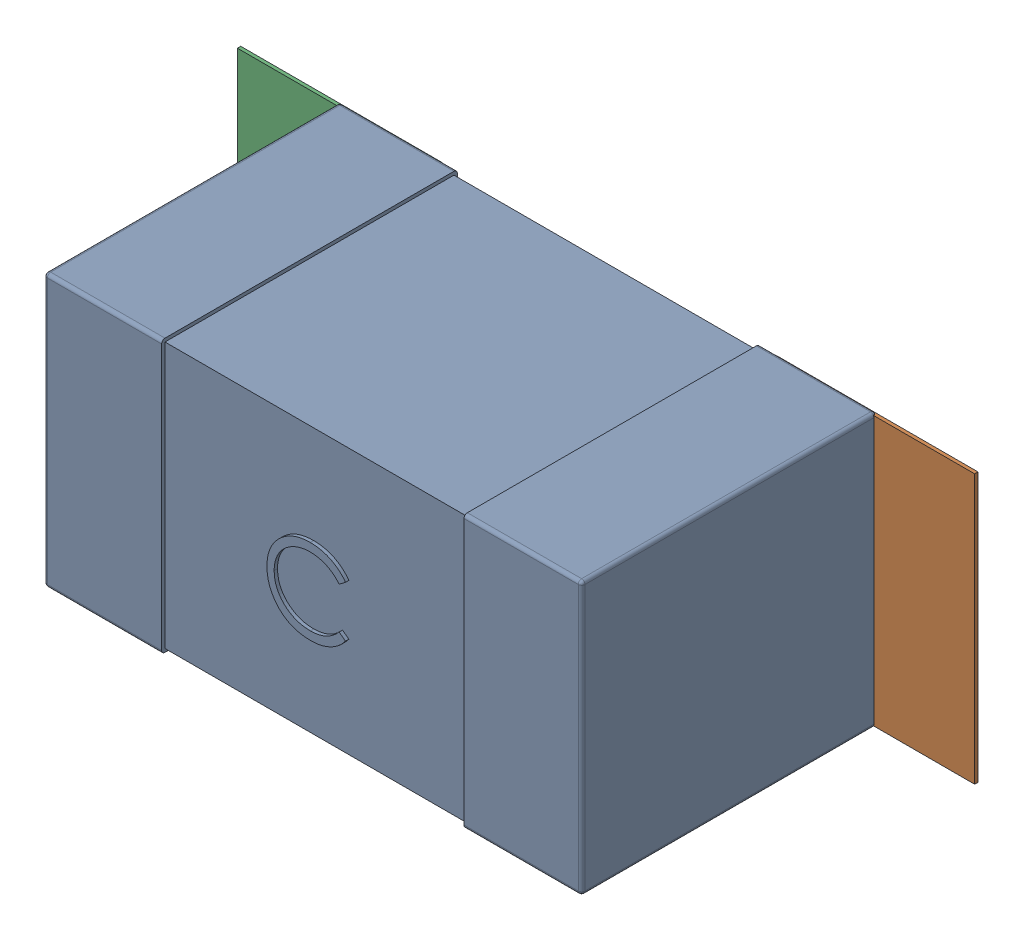
SolidWorks assembly C36, configuration Défaut. Lengths in mm.
Overall size (2.19 0.81 0.88).
5 component instances, 2 part files, 0 mates.
Components (placement in the parent):
- 0603_C-1: 0603_C [Défaut] at (8.9379 -9.0298 0) x (1 0 0) z (0 0 1) size (1.6 0.81 0.88)
- 6634915696-1: 6634915696 [Défaut] at (10.1879 -9.0298 0) size (0.6 0.8 0.01)
  - Extruded_497-1: Extruded_497 [Défaut] at origin size (0.6 0.8 0.01)
- 6634915696-2: 6634915696 [Défaut] at (8.593 -9.0298 0) size (0.6 0.8 0.01)
  - Extruded_497-1: Extruded_497 [Défaut] at origin size (0.6 0.8 0.01)
